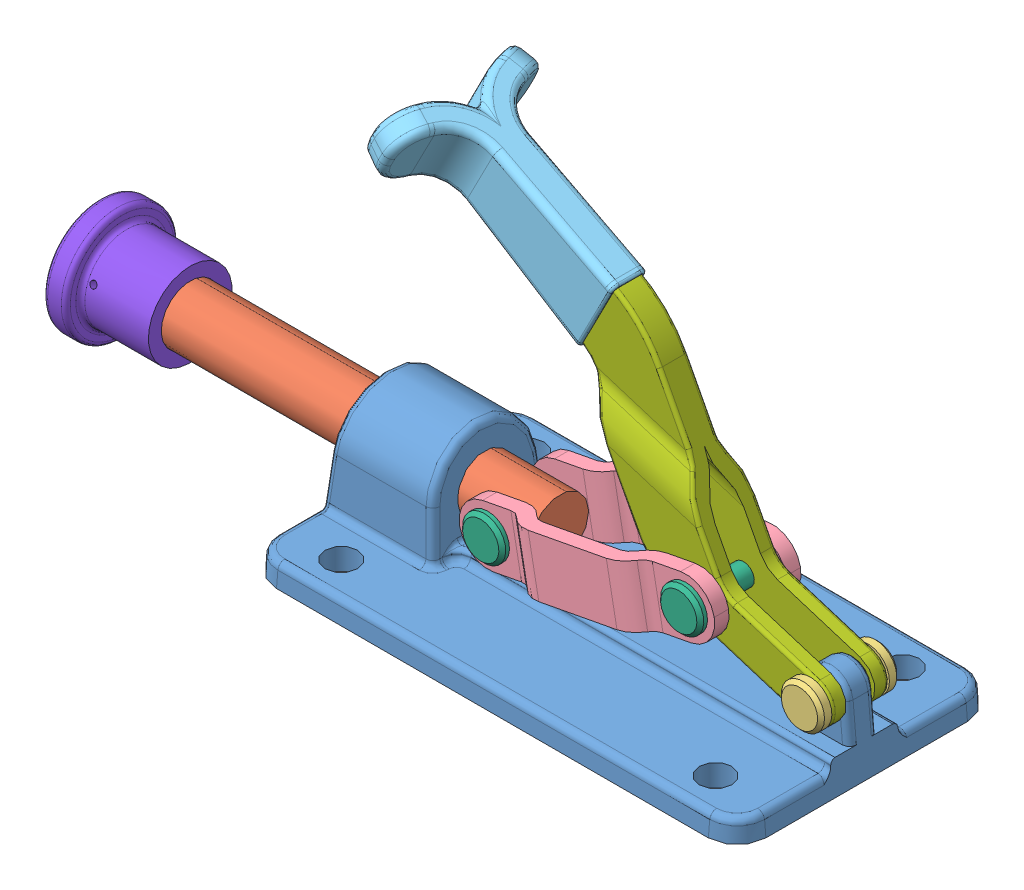
SolidWorks assembly drill_fixture, configuration Default. Lengths in mm.
Overall size (181.03 91.91 57.15).
10 component instances, 8 part files, 21 mates.
Components (placement in the parent):
- 143-001-1: 143-001 [Default] at (-60.9316 11.7502 0) size (107.95 26.11 57.15)
- 143-003-1: 143-003 [Default] at (-115.9004 26.0377 0) size (95.25 12.7 12.7)
- 143-007-1: 143-007 [Default] at (40.9264 26.7384 0) x (0 0 1) z (-0.989457 0.144826 0) size (17.46 9.53 9.53)
- 145-005-2: 145-005 [Default] at (-5.1621 30.1658 -6.35) x (-0.982599 -0.185741 0) z (0 0 -1) size (57.15 12.7 6.35)
- 143-004-1: 143-004 [Default] at (40.9264 26.7384 0) x (0.954734 -0.29746 0) z (0 0 1) size (44.88 24.28 32.95)
- 145-005-3: 145-005 [Default] at (-5.1621 30.1658 6.35) x (0.982599 0.185741 0) z (0 0 1) size (57.15 12.7 6.35)
- 143-006-1: 143-006 [Default] at (-27.0004 26.0377 0) x (0 0 1) z (-0.996665 -0.081604 0) size (22.23 9.53 9.53)
- 143-006-2: 143-006 [Default] at (16.6761 34.2939 0) x (0 0 1) z (-0.996665 -0.081604 0) size (22.23 9.53 9.53)
- 143-002-1: 143-002 [Default] at (40.9264 26.7384 0) x (0.954734 -0.29746 0) z (0 0 1) size (109.02 49.76 31.42)
- clamp end-f-1: clamp end-f [Default] at (-117.1737 26.0377 0) x (0 0.382918 0.923783) z (-1 0 0) size (24.92 24.92 20)
Mates (geometry in assembly coordinates):
- Concentric2: concentric anti-aligned: cylinder of 143-001-1 through (-60.9317 26.0377 0) axis (1 0 0) radius 6.35; cylinder of 143-003-1 through (-20.6504 26.0377 0) axis (-1 0 0) radius 6.35
- Concentric5: concentric anti-aligned: cylinder of 143-003-1 through (-27.0004 26.0377 -6.35) axis (0 0 1) radius 2.3813; cylinder of 145-005-2 through (-27.0004 26.0377 -6.35) axis (0 0 -1) radius 2.3813
- Coincident16: coincident anti-aligned: plane of 145-005-3 through (-34.4194 31.0977 9.525) normal (0 0 1); plane of 143-006-1 through (-27.389 30.7843 9.525) normal (0 0 -1)
- Concentric22: concentric anti-aligned: cylinder of 145-005-3 through (-27.0004 26.0377 12.7) axis (0 0 1) radius 6.35; cylinder of 143-006-1 through (-27.0004 26.0377 0) axis (0 0 -1) radius 2.3813
- Coincident17: coincident anti-aligned: plane of 145-005-3 through (21.7362 41.7128 9.525) normal (0 0 1); plane of 143-006-2 through (16.2875 39.0405 9.525) normal (0 0 -1)
- Concentric23: concentric anti-aligned: cylinder of 145-005-3 through (16.6761 34.2939 6.35) axis (0 0 1) radius 2.3813; cylinder of 143-006-2 through (16.6761 34.2939 0) axis (0 0 -1) radius 2.3813
- Concentric25: concentric aligned: cylinder of 145-005-3 through (-27.0004 26.0377 12.7) axis (0 0 1) radius 6.35; cylinder of 143-003-1 through (-27.0004 26.0377 -6.35) axis (0 0 1) radius 2.3813
- Concentric30: concentric aligned: cylinder of 143-001-1 through (40.9264 26.7384 -28.575) axis (0 0 1) radius 3.175; cylinder of 143-002-1 through (40.9264 26.7384 -6.35) axis (0 0 1) radius 2.3813
- Coincident23: coincident anti-aligned: plane of 143-001-1 through (40.9264 26.7384 3.175) normal (0 0 1); plane of 143-002-1 through (-47.5875 49.3277 3.175) normal (0 0 -1)
- Coincident24: coincident anti-aligned: plane of 145-005-2 through (21.7362 41.7128 -6.35) normal (0 0 1); plane of 143-002-1 through (40.9264 26.7384 -6.35) normal (0 0 -1)
- Concentric31: concentric anti-aligned: cylinder of 145-005-2 through (16.6761 34.2939 -12.7) axis (0 0 -1) radius 6.35; cylinder of 143-002-1 through (16.6761 34.2939 -6.35) axis (0 0 1) radius 2.3813
- Coincident25: coincident anti-aligned: plane of 143-007-1 through (41.6161 31.4507 6.35) normal (0 0 -1); plane of 143-002-1 through (40.9264 26.7384 6.35) normal (0 0 1)
- Concentric32: concentric anti-aligned: cylinder of 143-007-1 through (40.9264 26.7384 0) axis (0 0 -1) radius 2.3813; cylinder of 143-002-1 through (40.9264 26.7384 -6.35) axis (0 0 1) radius 2.3813
- Distance8: distance = 0 mm anti-aligned: plane of 143-004-1 through (-40.032 73.578 -3.175) normal (0 0 1); plane of 143-002-1 through (-40.032 73.578 -3.175) normal (0 0 -1)
- Distance9: distance = 0 mm anti-aligned: plane of 143-004-1 through (-6.4169 81.3108 6.35) normal (-0.458729 -0.888576 0); plane of 143-002-1 through (-6.4169 81.3108 6.35) normal (0.458729 0.888576 0)
- Distance10: distance = 0 mm anti-aligned: plane of 143-004-1 through (-12.9782 66.7916 6.35) normal (0.534428 0.845214 0); plane of 143-002-1 through (-12.9782 66.7916 6.35) normal (-0.534428 -0.845214 0)
- Concentric33: concentric aligned: cylinder of 145-005-3 through (16.6761 34.2939 6.35) axis (0 0 1) radius 2.3813; cylinder of 143-002-1 through (16.6761 34.2939 -6.35) axis (0 0 1) radius 2.3813
- Coincident26: coincident anti-aligned: plane of 145-005-3 through (21.7362 41.7128 6.35) normal (0 0 -1); plane of 143-002-1 through (40.9264 26.7384 6.35) normal (0 0 1)
- Concentric44: concentric anti-aligned: cylinder of 145-005-2 through (16.6761 34.2939 -12.7) axis (0 0 -1) radius 6.35; cylinder of 143-002-1 through (16.6761 34.2939 -6.35) axis (0 0 1) radius 2.3813
- Concentric45: concentric anti-aligned: cylinder of 143-003-1 through (-20.6504 26.0377 0) axis (-1 0 0) radius 6.35; cylinder of clamp end-f-1 through (-115.9004 26.0377 0) axis (1 0 0) radius 6.4135
- Coincident27: coincident anti-aligned: plane of 143-003-1 through (-115.9004 26.0377 0) normal (-1 0 0); plane of clamp end-f-1 through (-115.9004 28.4935 5.9247) normal (1 0 0)
